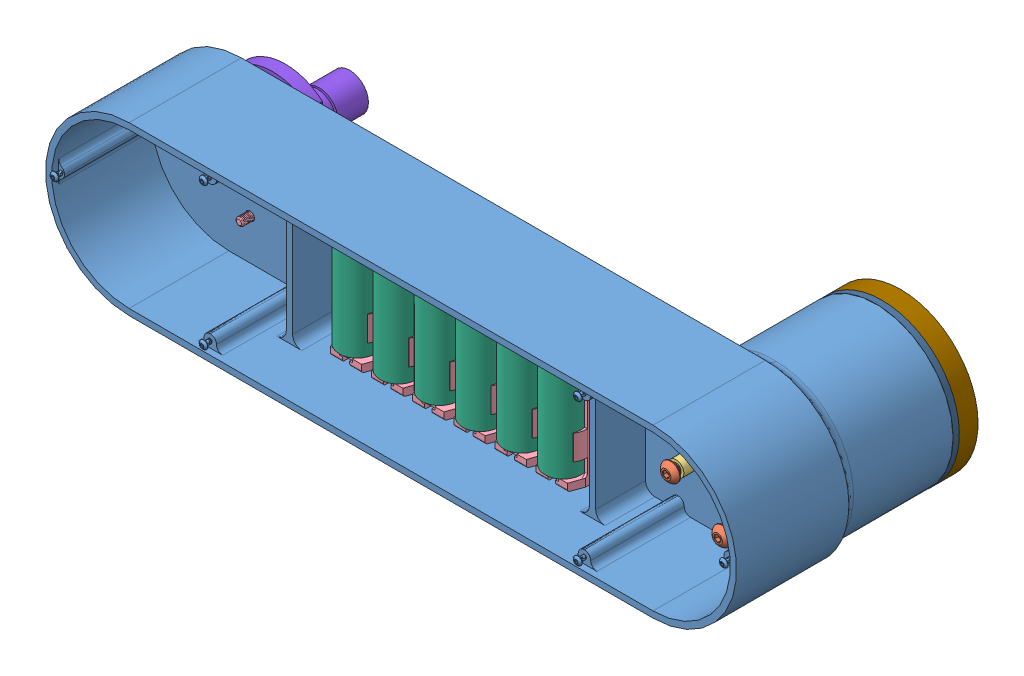
SolidWorks assembly Motor Link, configuration Default. Lengths in mm.
Overall size (351.79 85.09 127.3).
68 component instances, 28 part files, 118 mates.
Components (placement in the parent):
- Motor Link Frame-1: Motor Link Frame [Default] at (-50.4139 21.6178 -80.676) size (351.79 85.09 113.36)
- EC60 Motor-1: EC60 Motor [Default] at (-50.4139 21.6178 -74.326) x (0 0 1) z (0.866025 0.5 0) size (61.3 68 68) (hidden)
- Magnet Encoders E3-X-750-X-H-D-X-1: Magnet Encoders E3-X-750-X-H-D-X [Default] at (216.2861 21.6178 -70.897) x (0 -1 0) z (-1 0 0) size (55.98 16.26 66.52) (hidden)
- EM237 Magnet-1: EM237 Magnet [Default] at (216.2861 21.6178 -135.4915) x (0.985716 -0.168418 0) z (0.168418 0.985716 0) size (60.08 25.02 60.08)
- magnet holder-1: magnet holder [Default] at (219.7691 19.6509 -122.982) x (0.870755 -0.491717 0) z (-0.491717 -0.870755 0) size (50.8 63.9 50.6)
- PCB_Battery Assembly-3: PCB_Battery Assembly [Default] at (168.3898 -0.0136 45.5715) x (1 0 0) z (0 1 0) size (138.43 24.87 77.22)
  - Battery Holder - keystone-PN1043-1: Battery Holder - keystone-PN1043 [Default] at (-125.3925 103.3982 18.9155) x (1 0 0) z (0 0 -1) size (20.65 18.93 77.14)
  - Battery PCB-1: Battery PCB [Default] at (-148.3186 115.135 -16.9005) x (1 0 0) z (0 -1 0) size (138.43 77.06 1.59)
  - battery_6612-1: battery_6612 [Default] at (-117.0385 104.4035 -11.3639) x (-0.413992 0.91028 0) z (0.91028 0.413992 0) size (18.3 65.05 18.3)
  - battery_6612-2: battery_6612 [Default] at (-137.9935 104.4035 54.6265) x (-0.916106 0.400937 0) z (-0.400937 -0.916106 0) size (18.3 65.05 18.3)
  - Battery Holder - keystone-PN1043-2: Battery Holder - keystone-PN1043 [Default] at (-129.6396 103.3982 24.3471) x (-1 0 0) z (0 0 1) size (20.65 18.93 77.14)
  - Battery Holder - keystone-PN1043-3: Battery Holder - keystone-PN1043 [Default] at (-104.4375 103.3982 18.9155) x (1 0 0) z (0 0 -1) size (20.65 18.93 77.14)
  - battery_6612-3: battery_6612 [Default] at (-96.0835 104.4035 -10.3735) x (1 0 0) z (0 -1 0) size (18.3 65.05 18.3)
  - Battery Holder - keystone-PN1043-4: Battery Holder - keystone-PN1043 [Default] at (-83.4825 103.3982 18.9155) x (1 0 0) z (0 0 -1) size (20.65 18.93 77.14)
  - Battery Holder - keystone-PN1043-5: Battery Holder - keystone-PN1043 [Default] at (-45.8196 103.3982 24.3471) x (-1 0 0) z (0 0 1) size (20.65 18.93 77.14)
  - Battery Holder - keystone-PN1043-6: Battery Holder - keystone-PN1043 [Default] at (-41.5725 103.3982 18.9155) x (1 0 0) z (0 0 -1) size (20.65 18.93 77.14)
  - battery_6612-4: battery_6612 [Default] at (-75.1285 104.4035 -11.3639) x (-0.923728 -0.383049 0) z (-0.383049 0.923728 0) size (18.3 65.05 18.3)
  - battery_6612-5: battery_6612 [Default] at (-54.1735 104.4035 54.6265) x (-1 0 0) z (0 -1 0) size (18.3 65.05 18.3)
  - battery_6612-6: battery_6612 [Default] at (-33.2185 104.4035 -11.3639) x (-0.923728 -0.383049 0) z (-0.383049 0.923728 0) size (18.3 65.05 18.3)
- carrier_shaft-1: carrier_shaft [Default] at (-50.4139 39.1178 -75.596) x (-0.887515 0.46078 0) z (-0.46078 -0.887515 0) size (9 25.81 9)
- carrier_shaft-2: carrier_shaft [Default] at (-50.4139 4.1178 -75.596) x (-0.791269 0.611469 0) z (-0.611469 -0.791269 0) size (9 25.81 9)
- Shaft_Carrier_Combined-1: Shaft_Carrier_Combined [Default] at (-50.4139 21.6178 -103.1385) x (0 1 0) z (-1 0 0) size (57.15 55.17 57.15)
- Delrin_Ring-1: Delrin_Ring [Default] at (216.2861 21.6178 -149.5885) x (1 0 0) z (0 -1 0) size (78.74 9.53 78.74)
- Neoprene Ring-1: Neoprene Ring [Default] at (216.2861 21.6178 -140.0635) x (1 0 0) z (0 -1 0) size (78.74 3.17 78.74)
- Motor Link Acrylic Cover-1: Motor Link Acrylic Cover [Default] at (216.2861 21.6178 -26.701) x (-1 0 0) z (0 1 0) size (345.44 3.17 78.74) (hidden)
- Slip Ring M322M1-0600-1: Slip Ring M322M1-0600 [Default] at (216.2861 21.6178 -50.305) x (-0.866025 -0.5 0) z (0 0 -1) size (44 44 48) (hidden)
- bearing_8mmID_mcmaster_7804K115-1: bearing_8mmID_mcmaster_7804K115 [7804K115] at (-50.4139 39.1178 -78.926) x (-0.923728 -0.383049 0) z (0 0 -1) size (12 12 3.5)
- bearing_8mmID_mcmaster_7804K115-2: bearing_8mmID_mcmaster_7804K115 [7804K115] at (-50.4139 4.1178 -78.926) x (0.919429 -0.393256 0) z (0 0 -1) size (12 12 3.5)
- Bearing-I8mmO16mm-1: Bearing-I8mmO16mm [7804K117] at (-50.4139 4.1178 -99.051) x (0.999987 0.005155 0) z (0 0 1) size (16 16 5)
- Bearing-I8mmO16mm-2: Bearing-I8mmO16mm [7804K117] at (-50.4139 39.1178 -99.051) x (0.862389 -0.506247 0) z (0 0 -1) size (16 16 5)
- Bearing - .750-1: Bearing - .750 [3760T241] at (216.2861 21.6178 -86.2323) x (-0.324728 0.945808 0) z (0 0 1) size (41.27 41.27 11.11)
- Bearing - .750-2: Bearing - .750 [3760T241] at (216.2861 21.6178 -97.3448) x (0.923728 0.383049 0) z (0 0 -1) size (41.27 41.27 11.11)
- 10-32 Button Cap Thread Locking Screw-1: 10-32 Button Cap Thread Locking Screw [92360A244] at (-26.9189 13.9978 -89.5914) x (-0.890787 -0.45442 0) z (0 0 -1) size (9.17 9.17 12.51)
- 10-32 Button Cap Thread Locking Screw-2: 10-32 Button Cap Thread Locking Screw [92360A244] at (-73.9089 13.9978 -89.5914) x (-0.923728 -0.383049 0) z (0 0 -1) size (9.17 9.17 12.51)
- 10-32 Button Cap Thread Locking Screw-3: 10-32 Button Cap Thread Locking Screw [92360A244] at (-26.9189 29.2378 -89.5914) x (-0.923728 -0.383049 0) z (0 0 -1) size (9.17 9.17 12.51)
- 10-32 Button Cap Thread Locking Screw-4: 10-32 Button Cap Thread Locking Screw [92360A244] at (-73.9089 29.2378 -89.5914) x (-0.923728 -0.383049 0) z (0 0 -1) size (9.17 9.17 12.51)
- 1.625 Bore Internal Retaining Ring-1: 1.625 Bore Internal Retaining Ring [99142A560] at (216.2861 21.6178 -103.0534) x (1 0 0) z (0 -1 0) size (45.82 1.57 43.68)
- M8_L16mm Screws-1: M8_L16mm Screws [91760A423] at (216.2861 21.6178 -132.632) x (0.923728 0.383049 0) z (0 0 -1) size (13 13 24.67)
- .75 Bore External Retaining Ring-1: .75 Bore External Retaining Ring [97633A250] at (216.2861 21.6178 -80.1426) x (0 0 1) z (0.923728 0.383049 0) size (1.07 23.39 21.18)
- Dowel Pin - .0625-1: Dowel Pin - .0625 [97395A414] at (216.2861 57.8128 -133.7135) x (0 0 1) z (-1 0 0) size (19.05 1.59 1.59)
- Dowel Pin - .0625-2: Dowel Pin - .0625 [97395A414] at (252.4811 21.6178 -133.7135) x (0 0 1) z (-1 0 0) size (19.05 1.59 1.59)
- Dowel Pin - .0625-3: Dowel Pin - .0625 [97395A414] at (216.2861 -14.5772 -133.7135) x (0 0 1) z (-1 0 0) size (19.05 1.59 1.59)
- Dowel Pin - .0625-4: Dowel Pin - .0625 [97395A414] at (180.0911 21.6178 -133.7135) x (0 0 1) z (-1 0 0) size (19.05 1.59 1.59)
- 2-56 Screw-1: 2-56 Screw [98164A427] at (-88.1964 21.6178 -22.3576) size (4.17 4.17 10.95)
- 2-56 Screw-2: 2-56 Screw [98164A427] at (-12.3139 57.8128 -22.3576) size (4.17 4.17 10.95)
- 2-56 Screw-3: 2-56 Screw [98164A427] at (-12.3139 -14.5772 -22.3576) size (4.17 4.17 10.95)
- 2-56 Screw-4: 2-56 Screw [98164A427] at (178.1861 -14.5772 -22.3576) size (4.17 4.17 10.95)
- 2-56 Screw-5: 2-56 Screw [98164A427] at (252.4811 21.6178 -22.3576) size (4.17 4.17 10.95)
- 2-56 Screw-6: 2-56 Screw [98164A427] at (178.1861 57.8128 -22.3576) size (4.17 4.17 10.95)
- M5 Screws-1: M5 Screws [91352A131] at (225.0361 36.7732 -47.555) size (9.5 9.5 13.21)
- M5 Screws-2: M5 Screws [91352A131] at (225.0361 6.4623 -47.555) size (9.5 9.5 13.21)
- M5 Screws-3: M5 Screws [91352A131] at (198.7861 21.6178 -47.555) size (9.5 9.5 13.21)
- M5 Nylon Spacer-1: M5 Nylon Spacer [93657A042] at (198.7861 21.6178 -55.705) size (8 8 6)
- M5 Nylon Spacer-2: M5 Nylon Spacer [93657A042] at (225.0361 6.4623 -55.705) x (-0.923728 -0.383049 0) z (0 0 -1) size (8 8 6)
- M5 Nylon Spacer-3: M5 Nylon Spacer [93657A042] at (225.0361 36.7732 -55.705) size (8 8 6)
- M4 Screw-1: M4 Screw [91502A123] at (-71.9139 21.6178 -68.676) size (7 7 12.31)
- M4 Screw-2: M4 Screw [91502A123] at (-39.6639 40.2373 -68.676) size (7 7 12.31)
- M4 Screw-3: M4 Screw [91502A123] at (-39.6639 2.9982 -68.676) size (7 7 12.31)
- 4-40 Screws-1: 4-40 Screws [92949A108] at (216.2861 -1.3946 -69.3984) size (5.41 5.41 11.35)
- 4-40 Screws-2: 4-40 Screws [92949A108] at (216.2861 44.6302 -69.3984) size (5.41 5.41 11.35)
- 2-56 Screw-7: 2-56 Screw [98164A427] at (16.8961 53.7996 -66.8076) size (4.17 4.17 10.95)
- 2-56 Screw-8: 2-56 Screw [98164A427] at (148.9761 53.7996 -66.8076) size (4.17 4.17 10.95)
- 2-56 Screw-9: 2-56 Screw [98164A427] at (148.9761 -10.564 -66.8076) size (4.17 4.17 10.95)
- 2-56 Screw-10: 2-56 Screw [98164A427] at (16.8961 -10.564 -66.8076) size (4.17 4.17 10.95)
- #2 Spacer-1: #2 Spacer [94639A188] at (16.8961 -10.564 -71.9448) x (0.923728 0.383049 0) z (0 0 -1) size (6.35 6.35 4.76)
- #2 Spacer-2: #2 Spacer [94639A188] at (148.9761 -10.564 -71.9448) x (0.923728 0.383049 0) z (0 0 -1) size (6.35 6.35 4.76)
- #2 Spacer-3: #2 Spacer [94639A188] at (148.9761 53.7996 -71.9448) x (0.923728 0.383049 0) z (0 0 -1) size (6.35 6.35 4.76)
- #2 Spacer-4: #2 Spacer [94639A188] at (16.8961 53.7996 -71.9448) x (0.923728 0.383049 0) z (0 0 -1) size (6.35 6.35 4.76)
Mates (geometry in assembly coordinates):
- Coincident2: coincident aligned: line of Motor Link Frame-1 through (-50.4139 21.6178 -80.676) axis (0 0 1); line of EC60 Motor-1 through (-50.4139 21.6178 -95.9581) axis (0 0 1)
- Coincident3: coincident anti-aligned: plane of Motor Link Frame-1 through (-50.4139 21.6178 -74.326) normal (0 0 1); plane of EC60 Motor-1
- Coincident4: coincident aligned: plane of Motor Link Frame-1 through (-50.4139 21.6178 -80.676) normal (0 0 -1); plane of bearing_8mmID_mcmaster_7804K115-1 through (-50.4139 39.1178 -80.676) normal (0 0 -1)
- Coincident5: coincident aligned: line of Motor Link Frame-1 through (-50.4139 39.1178 -80.676) axis (0 0 1); line of bearing_8mmID_mcmaster_7804K115-1 through (-50.4139 39.1178 -77.176) axis (0 0 1)
- Coincident6: coincident aligned: plane of Motor Link Frame-1 through (-50.4139 21.6178 -80.676) normal (0 0 -1); plane of bearing_8mmID_mcmaster_7804K115-2 through (-50.4139 4.1178 -80.676) normal (0 0 -1)
- Coincident7: coincident aligned: line of Motor Link Frame-1 through (-50.4139 4.1178 -80.676) axis (0 0 1); line of bearing_8mmID_mcmaster_7804K115-2 through (-50.4139 4.1178 -77.176) axis (0 0 1)
- Concentric1: concentric: point of Motor Link Frame-1; cylinder of Magnet Encoders E3-X-750-X-H-D-X-1 through (216.2861 21.6178 -64.3438) axis (0 0 1) radius 9.5263
- Coincident11: coincident anti-aligned: plane of Motor Link Frame-1 through (-50.4139 21.6178 -74.326) normal (0 0 1); plane of Magnet Encoders E3-X-750-X-H-D-X-1 through (216.2861 21.6178 -74.326) normal (0 0 -1)
- Perpendicular1: perpendicular: plane of Motor Link Frame-1 through (-50.4139 64.1628 -80.676) normal (0 1 0); plane of Magnet Encoders E3-X-750-X-H-D-X-1 through (183.0629 6.0623 -72.4718) normal (-0.999391 0 0.034899)
- Concentric2: concentric aligned: line of Motor Link Frame-1 through (216.2861 21.6178 -136.8885) axis (0 0 1); cylinder of EM237 Magnet-1 through (216.2861 21.6178 -148.001) axis (0 0 1) radius 30.0419
- Coincident16: coincident anti-aligned: line of Motor Link Frame-1 through (216.2861 21.6178 -136.8885) axis (0 0 1); line of magnet holder-1 through (216.2861 21.6178 -59.086) axis (0 0 -1)
- Coincident26: coincident aligned: line of carrier_shaft-1 through (-50.4139 39.1178 -92.596) axis (0 0 1); line of Motor Link Frame-1 through (-50.4139 39.1178 -80.676) axis (0 0 1)
- Coincident29: coincident aligned: line of Motor Link Frame-1 through (-50.4139 4.1178 -80.676) axis (0 0 1); line of carrier_shaft-2 through (-50.4139 4.1178 -92.596) axis (0 0 1)
- Coincident37: coincident aligned: line of Motor Link Frame-1 through (-50.4139 21.6178 -80.676) axis (0 0 1); line of Shaft_Carrier_Combined-1 through (-50.4139 21.6178 -135.841) axis (0 0 1)
- Coincident38: coincident aligned: line of Motor Link Frame-1 through (-50.4139 4.1178 -80.676) axis (0 0 1); line of Shaft_Carrier_Combined-1 through (-50.4139 4.1178 -101.551) axis (0 0 1)
- Coincident39: coincident aligned: line of Motor Link Frame-1 through (-50.4139 39.1178 -80.676) axis (0 0 1); line of Shaft_Carrier_Combined-1 through (-50.4139 39.1178 -101.551) axis (0 0 1)
- Coincident41: coincident anti-aligned: plane of Motor Link Frame-1 through (-50.4139 21.6178 -80.676) normal (0 0 -1); plane of Shaft_Carrier_Combined-1
- Coincident42: coincident anti-aligned: line of Shaft_Carrier_Combined-1 through (-50.4139 4.1178 -101.551) axis (0 0 1); line of Bearing-I8mmO16mm-1 through (-50.4139 4.1178 -101.551) axis (0 0 -1)
- Coincident44: coincident aligned: line of Shaft_Carrier_Combined-1 through (-50.4139 39.1178 -101.551) axis (0 0 1); line of Bearing-I8mmO16mm-2 through (-50.4139 39.1178 -96.551) axis (0 0 1)
- Coincident46: coincident anti-aligned: plane of Motor Link Frame-1 through (-50.4139 39.1178 -75.596) normal (0 0 -1); plane of carrier_shaft-1 through (-50.4139 39.1178 -75.596) normal (0 0 1)
- Coincident47: coincident anti-aligned: plane of Motor Link Frame-1 through (-50.4139 4.1178 -75.596) normal (0 0 -1); plane of carrier_shaft-2 through (-50.4139 4.1178 -75.596) normal (0 0 1)
- Coincident51: coincident anti-aligned: plane of Shaft_Carrier_Combined-1 through (-50.4139 4.1178 -101.551) normal (0 0 1); plane of Bearing-I8mmO16mm-1 through (-50.4538 11.8676 -101.551) normal (0 0 -1)
- Coincident52: coincident anti-aligned: plane of Shaft_Carrier_Combined-1 through (-50.4139 39.1178 -101.551) normal (0 0 1); plane of Bearing-I8mmO16mm-2 through (-54.3373 32.4342 -101.551) normal (0 0 -1)
- Coincident53: coincident aligned: line of Motor Link Frame-1 through (-26.9189 13.9978 -76.866) axis (0 0 -1); line of 10-32 Button Cap Thread Locking Screw-1 through (-26.9189 13.9978 -77.501) axis (0 0 -1)
- Coincident54: coincident anti-aligned: plane of Shaft_Carrier_Combined-1 through (-50.4139 21.6178 -87.026) normal (0 0 -1); plane of 10-32 Button Cap Thread Locking Screw-1 through (-24.8355 9.9138 -87.026) normal (0 0 1)
- Coincident55: coincident anti-aligned: plane of Shaft_Carrier_Combined-1 through (-50.4139 21.6178 -87.026) normal (0 0 -1); plane of 10-32 Button Cap Thread Locking Screw-3 through (-25.1627 25.0027 -87.026) normal (0 0 1)
- Coincident56: coincident aligned: line of Motor Link Frame-1 through (-26.9189 29.2378 -76.866) axis (0 0 -1); line of 10-32 Button Cap Thread Locking Screw-3 through (-26.9189 29.2378 -77.501) axis (0 0 -1)
- Coincident57: coincident aligned: line of Motor Link Frame-1 through (-73.9089 13.9978 -76.866) axis (0 0 -1); line of 10-32 Button Cap Thread Locking Screw-2 through (-73.9089 13.9978 -77.501) axis (0 0 -1)
- Coincident58: coincident anti-aligned: plane of Shaft_Carrier_Combined-1 through (-50.4139 21.6178 -87.026) normal (0 0 -1); plane of 10-32 Button Cap Thread Locking Screw-2 through (-72.1527 9.7627 -87.026) normal (0 0 1)
- Coincident59: coincident aligned: line of Motor Link Frame-1 through (-73.9089 29.2378 -76.866) axis (0 0 -1); line of 10-32 Button Cap Thread Locking Screw-4 through (-73.9089 29.2378 -77.501) axis (0 0 -1)
- Coincident60: coincident anti-aligned: plane of Shaft_Carrier_Combined-1 through (-50.4139 21.6178 -87.026) normal (0 0 -1); plane of 10-32 Button Cap Thread Locking Screw-4 through (-72.1527 25.0027 -87.026) normal (0 0 1)
- Coincident61: coincident anti-aligned: line of Motor Link Frame-1 through (216.2861 21.6178 -136.8885) axis (0 0 1); line of Bearing - .750-1 through (216.2861 21.6178 -91.7885) axis (0 0 -1)
- Coincident62: coincident anti-aligned: plane of Motor Link Frame-1 through (216.2861 21.6178 -80.676) normal (0 0 -1); plane of Bearing - .750-1 through (197.2925 15.0966 -80.676) normal (0 0 1)
- Concentric6: concentric aligned: line of Motor Link Frame-1 through (216.2861 21.6178 -136.8885) axis (0 0 1); cylinder of 1.625 Bore Internal Retaining Ring-1 through (216.2861 21.6178 -104.6282) axis (0 0 1) radius 22.9108
- Concentric8: concentric anti-aligned: line of Motor Link Frame-1 through (216.2861 21.6178 -136.8885) axis (0 0 1); cylinder of Bearing - .750-2 through (216.2861 21.6178 -102.901) axis (0 0 -1) radius 9.525
- Coincident68: coincident anti-aligned: plane of Motor Link Frame-1 through (216.2861 21.6178 -104.6282) normal (0 0 1); plane of 1.625 Bore Internal Retaining Ring-1 through (227.2749 4.8737 -104.6282) normal (0 0 -1)
- Coincident69: coincident anti-aligned: plane of Bearing - .750-1 through (197.2925 15.0966 -91.7885) normal (0 0 -1); plane of Bearing - .750-2 through (223.9785 3.0676 -91.7885) normal (0 0 1)
- Coincident71: coincident anti-aligned: plane of magnet holder-1 through (227.3447 15.3729 -102.901) normal (0 0 1); plane of Bearing - .750-2 through (221.5551 8.9115 -102.901) normal (0 0 -1)
- Coincident72: coincident anti-aligned: plane of EM237 Magnet-1 through (216.2861 21.6178 -122.982) normal (0 0 1); plane of magnet holder-1 through (219.7691 19.6509 -122.982) normal (0 0 -1)
- Concentric9: concentric aligned: line of magnet holder-1 through (216.2861 21.6178 -59.086) axis (0 0 -1); cylinder of M8_L16mm Screws-1 through (216.2861 21.6178 -108.632) axis (0 0 -1) radius 6.5
- Coincident74: coincident anti-aligned: plane of magnet holder-1 through (222.161 18.3002 -116.632) normal (0 0 1); plane of M8_L16mm Screws-1 through (216.2861 21.6178 -116.632) normal (0 0 -1)
- Concentric10: concentric aligned: line of magnet holder-1 through (216.2861 21.6178 -59.086) axis (0 0 -1); cylinder of .75 Bore External Retaining Ring-1 through (216.2861 21.6178 -79.6092) axis (0 0 -1) radius 8.8011
- Coincident77: coincident anti-aligned: plane of magnet holder-1 through (216.2861 21.6178 -80.676) normal (0 0 1); plane of .75 Bore External Retaining Ring-1 through (216.2861 21.6178 -80.676) normal (0 0 -1)
- Coincident78: coincident anti-aligned: plane of Motor Link Frame-1 through (216.2861 21.6178 -136.8885) normal (0 0 -1); plane of Neoprene Ring-1 through (216.2861 21.6178 -136.8885) normal (0 0 1)
- Concentric11: concentric anti-aligned: line of Motor Link Frame-1 through (216.2861 21.6178 -136.8885) axis (0 0 1); cylinder of Neoprene Ring-1 through (216.2861 21.6178 -136.8885) axis (0 0 -1) radius 33.02
- Concentric12: concentric anti-aligned: line of Motor Link Frame-1 through (216.2861 21.6178 -136.8885) axis (0 0 1); cylinder of Delrin_Ring-1 through (216.2861 21.6178 -140.0635) axis (0 0 -1) radius 33.02
- Coincident81: coincident anti-aligned: plane of Delrin_Ring-1 through (216.2861 21.6178 -140.0635) normal (0 0 1); plane of Neoprene Ring-1 through (216.2861 21.6178 -140.0635) normal (0 0 -1)
- Concentric13: concentric aligned: cylinder of Motor Link Frame-1 through (252.4811 21.6178 -124.1885) axis (0 0 -1) radius 0.7937; cylinder of Neoprene Ring-1 through (252.4811 21.6178 -136.8885) axis (0 0 -1) radius 0.7937
- Concentric14: concentric aligned: cylinder of Motor Link Frame-1 through (252.4811 21.6178 -124.1885) axis (0 0 -1) radius 0.7937; cylinder of Delrin_Ring-1 through (252.4811 21.6178 -140.0635) axis (0 0 -1) radius 0.7937
- Concentric15: concentric anti-aligned: cylinder of Motor Link Frame-1 through (252.4811 21.6178 -124.1885) axis (0 0 -1) radius 0.7937; cylinder of Dowel Pin - .0625-2 through (252.4811 21.6178 -143.2385) axis (0 0 1) radius 0.7937
- Coincident82: coincident anti-aligned: plane of Motor Link Frame-1 through (252.4811 21.6178 -124.1885) normal (0 0 -1); plane of Dowel Pin - .0625-2 through (252.4811 21.6178 -124.1885) normal (0 0 1)
- Concentric16: concentric anti-aligned: cylinder of Motor Link Frame-1 through (216.2861 57.8128 -124.1885) axis (0 0 -1) radius 0.7937; cylinder of Dowel Pin - .0625-1 through (216.2861 57.8128 -143.2385) axis (0 0 1) radius 0.7937
- Coincident83: coincident anti-aligned: plane of Motor Link Frame-1 through (216.2861 57.8128 -124.1885) normal (0 0 -1); plane of Dowel Pin - .0625-1 through (216.2861 57.8128 -124.1885) normal (0 0 1)
- Concentric17: concentric anti-aligned: cylinder of Motor Link Frame-1 through (180.0911 21.6178 -124.1885) axis (0 0 -1) radius 0.7937; cylinder of Dowel Pin - .0625-4 through (180.0911 21.6178 -143.2385) axis (0 0 1) radius 0.7937
- Coincident84: coincident anti-aligned: plane of Motor Link Frame-1 through (180.0911 21.6178 -124.1885) normal (0 0 -1); plane of Dowel Pin - .0625-4 through (180.0911 21.6178 -124.1885) normal (0 0 1)
- Concentric18: concentric anti-aligned: cylinder of Motor Link Frame-1 through (216.2861 -14.5772 -124.1885) axis (0 0 -1) radius 0.7937; cylinder of Dowel Pin - .0625-3 through (216.2861 -14.5772 -143.2385) axis (0 0 1) radius 0.7937
- Coincident85: coincident anti-aligned: plane of Motor Link Frame-1 through (216.2861 -14.5772 -124.1885) normal (0 0 -1); plane of Dowel Pin - .0625-3 through (216.2861 -14.5772 -124.1885) normal (0 0 1)
- Coincident86: coincident anti-aligned: plane of Motor Link Acrylic Cover-1 through (216.2861 21.6178 -26.701) normal (0 0 -1); plane of Motor Link Frame-1 through (-50.4139 21.6178 -26.701) normal (0 0 1)
- Concentric26: concentric anti-aligned: cylinder of Motor Link Frame-1 through (-88.1964 21.6178 -26.701) axis (0 0 1) radius 0.889; cylinder of Motor Link Acrylic Cover-1 through (-88.1964 21.6178 -23.526) axis (0 0 -1) radius 1.0922
- Concentric27: concentric anti-aligned: cylinder of Motor Link Frame-1 through (252.4811 21.6178 -26.701) axis (0 0 1) radius 0.889; cylinder of Motor Link Acrylic Cover-1 through (252.4811 21.6178 -23.526) axis (0 0 -1) radius 1.0922
- Concentric28: concentric anti-aligned: cylinder of Motor Link Acrylic Cover-1 through (-88.1964 21.6178 -23.526) axis (0 0 -1) radius 1.0922; line of 2-56 Screw-1 through (-88.1964 21.6178 -33.051) axis (0 0 1)
- Coincident88: coincident anti-aligned: plane of Motor Link Acrylic Cover-1 through (216.2861 21.6178 -23.526) normal (0 0 1); plane of 2-56 Screw-1 through (-88.1964 19.535 -23.526) normal (0 0 -1)
- Concentric29: concentric anti-aligned: cylinder of Motor Link Acrylic Cover-1 through (-12.3139 57.8128 -23.526) axis (0 0 -1) radius 1.0922; line of 2-56 Screw-2 through (-12.3139 57.8128 -33.051) axis (0 0 1)
- Coincident90: coincident anti-aligned: plane of Motor Link Acrylic Cover-1 through (216.2861 21.6178 -23.526) normal (0 0 1); plane of 2-56 Screw-2 through (-12.3139 55.73 -23.526) normal (0 0 -1)
- Concentric30: concentric anti-aligned: cylinder of Motor Link Acrylic Cover-1 through (-12.3139 -14.5772 -23.526) axis (0 0 -1) radius 1.0922; line of 2-56 Screw-3 through (-12.3139 -14.5772 -33.051) axis (0 0 1)
- Coincident92: coincident anti-aligned: plane of Motor Link Acrylic Cover-1 through (216.2861 21.6178 -23.526) normal (0 0 1); plane of 2-56 Screw-3 through (-12.3139 -16.66 -23.526) normal (0 0 -1)
- Concentric31: concentric anti-aligned: cylinder of Motor Link Acrylic Cover-1 through (178.1861 -14.5772 -23.526) axis (0 0 -1) radius 1.0922; line of 2-56 Screw-4 through (178.1861 -14.5772 -33.051) axis (0 0 1)
- Coincident94: coincident anti-aligned: plane of Motor Link Acrylic Cover-1 through (216.2861 21.6178 -23.526) normal (0 0 1); plane of 2-56 Screw-4 through (178.1861 -16.66 -23.526) normal (0 0 -1)
- Concentric32: concentric anti-aligned: cylinder of Motor Link Acrylic Cover-1 through (178.1861 57.8128 -23.526) axis (0 0 -1) radius 1.0922; line of 2-56 Screw-6 through (178.1861 57.8128 -33.051) axis (0 0 1)
- Coincident96: coincident anti-aligned: plane of Motor Link Acrylic Cover-1 through (216.2861 21.6178 -23.526) normal (0 0 1); plane of 2-56 Screw-6 through (178.1861 55.73 -23.526) normal (0 0 -1)
- Concentric33: concentric anti-aligned: cylinder of Motor Link Acrylic Cover-1 through (252.4811 21.6178 -23.526) axis (0 0 -1) radius 1.0922; line of 2-56 Screw-5 through (252.4811 21.6178 -33.051) axis (0 0 1)
- Coincident98: coincident anti-aligned: plane of Motor Link Acrylic Cover-1 through (216.2861 21.6178 -23.526) normal (0 0 1); plane of 2-56 Screw-5 through (252.4811 19.535 -23.526) normal (0 0 -1)
- Distance2: distance = 6 mm anti-aligned: plane of Slip Ring M322M1-0600-1 through (197.2336 10.6178 -52.705) normal (0 0 -1); plane of Magnet Encoders E3-X-750-X-H-D-X-1 through (216.2861 21.6178 -58.705) normal (0 0 1)
- Concentric34: concentric aligned: line of Motor Link Frame-1 through (216.2861 21.6178 -136.8885) axis (0 0 1); cylinder of Slip Ring M322M1-0600-1 through (216.2861 21.6178 -66.705) axis (0 0 1) radius 3.8
- Concentric35: concentric aligned: cylinder of Slip Ring M322M1-0600-1 through (198.7861 21.6178 -50.305) axis (0 0 1) radius 2.75; cylinder of Magnet Encoders E3-X-750-X-H-D-X-1 through (198.7861 21.6178 -58.705) axis (0 0 1) radius 2.1
- Concentric36: concentric aligned: cylinder of Magnet Encoders E3-X-750-X-H-D-X-1 through (225.0361 6.4623 -58.705) axis (0 0 1) radius 2.1; cylinder of Slip Ring M322M1-0600-1 through (225.0361 6.4623 -50.305) axis (0 0 1) radius 2.75
- Concentric37: concentric aligned: cylinder of Magnet Encoders E3-X-750-X-H-D-X-1 through (225.0361 36.7732 -58.705) axis (0 0 1) radius 2.1; cylinder of Slip Ring M322M1-0600-1 through (225.0361 36.7732 -50.305) axis (0 0 1) radius 2.75
- Concentric38: concentric aligned: cylinder of Slip Ring M322M1-0600-1 through (225.0361 36.7732 -50.305) axis (0 0 1) radius 2.75; line of M5 Screws-1 through (225.0361 36.7732 -60.305) axis (0 0 1)
- Coincident102: coincident anti-aligned: plane of Slip Ring M322M1-0600-1 through (216.2861 21.6178 -50.305) normal (0 0 1); plane of M5 Screws-1 through (225.0361 32.0232 -50.305) normal (0 0 -1)
- Concentric39: concentric aligned: cylinder of Slip Ring M322M1-0600-1 through (225.0361 6.4623 -50.305) axis (0 0 1) radius 2.75; line of M5 Screws-2 through (225.0361 6.4623 -60.305) axis (0 0 1)
- Coincident104: coincident anti-aligned: plane of Slip Ring M322M1-0600-1 through (216.2861 21.6178 -50.305) normal (0 0 1); plane of M5 Screws-2 through (225.0361 1.7123 -50.305) normal (0 0 -1)
- Concentric40: concentric aligned: cylinder of Slip Ring M322M1-0600-1 through (198.7861 21.6178 -50.305) axis (0 0 1) radius 2.75; line of M5 Screws-3 through (198.7861 21.6178 -60.305) axis (0 0 1)
- Coincident106: coincident anti-aligned: plane of Slip Ring M322M1-0600-1 through (216.2861 21.6178 -50.305) normal (0 0 1); plane of M5 Screws-3 through (198.7861 16.8678 -50.305) normal (0 0 -1)
- Coincident107: coincident anti-aligned: plane of Magnet Encoders E3-X-750-X-H-D-X-1 through (216.2861 21.6178 -58.705) normal (0 0 1); plane of M5 Nylon Spacer-1 through (198.7861 21.6178 -58.705) normal (0 0 -1)
- Concentric42: concentric aligned: cylinder of Slip Ring M322M1-0600-1 through (225.0361 6.4623 -50.305) axis (0 0 1) radius 2.75; cylinder of M5 Nylon Spacer-2 through (225.0361 6.4623 -58.705) axis (0 0 1) radius 2.65
- Coincident108: coincident anti-aligned: plane of Magnet Encoders E3-X-750-X-H-D-X-1 through (216.2861 21.6178 -58.705) normal (0 0 1); plane of M5 Nylon Spacer-2 through (225.0361 6.4623 -58.705) normal (0 0 -1)
- Concentric43: concentric anti-aligned: cylinder of Slip Ring M322M1-0600-1 through (225.0361 36.7732 -50.305) axis (0 0 1) radius 2.75; cylinder of M5 Nylon Spacer-3 through (225.0361 36.7732 -52.705) axis (0 0 -1) radius 2.65
- Coincident109: coincident anti-aligned: plane of Slip Ring M322M1-0600-1 through (197.2336 10.6178 -52.705) normal (0 0 -1); plane of M5 Nylon Spacer-3 through (225.0361 36.7732 -52.705) normal (0 0 1)
- Concentric44: concentric anti-aligned: cylinder of Motor Link Frame-1 through (-39.6639 2.9982 -80.676) axis (0 0 -1) radius 4; circle of M4 Screw-3
- Coincident111: coincident anti-aligned: plane of Motor Link Frame-1 through (-37.4139 2.9982 -76.676) normal (0 0 -1); plane of M4 Screw-3 through (-39.6639 2.9982 -76.676) normal (0 0 1)
- Concentric45: concentric anti-aligned: cylinder of Motor Link Frame-1 through (-39.6639 40.2373 -80.676) axis (0 0 -1) radius 4; cylinder of M4 Screw-2 through (-39.6639 40.2373 -80.676) axis (0 0 1) radius 3.5
- Coincident112: coincident anti-aligned: plane of Motor Link Frame-1 through (-37.4139 40.2373 -76.676) normal (0 0 -1); plane of M4 Screw-2 through (-39.6639 40.2373 -76.676) normal (0 0 1)
- Concentric47: concentric anti-aligned: cylinder of Motor Link Frame-1 through (-71.9139 21.6178 -80.676) axis (0 0 -1) radius 4; cylinder of M4 Screw-1 through (-71.9139 21.6178 -80.676) axis (0 0 1) radius 3.5
- Coincident113: coincident anti-aligned: plane of Motor Link Frame-1 through (-69.6639 21.6178 -76.676) normal (0 0 -1); plane of M4 Screw-1 through (-71.9139 21.6178 -76.676) normal (0 0 1)
- Concentric48: concentric aligned: cylinder of Motor Link Frame-1 through (-71.9139 21.6178 -80.676) axis (0 0 -1) radius 4; cylinder of EC60 Motor-1 through (-71.9139 21.6178 -74.326) axis (0 0 -1) radius 1.65
- Concentric49: concentric anti-aligned: cylinder of Magnet Encoders E3-X-750-X-H-D-X-1 through (216.2861 -1.3946 -70.897) axis (0 0 -1) radius 1.4351; line of 4-40 Screws-1 through (216.2861 -1.3946 -80.422) axis (0 0 1)
- Coincident115: coincident anti-aligned: plane of Magnet Encoders E3-X-750-X-H-D-X-1 through (216.2861 21.6178 -70.897) normal (0 0 1); plane of 4-40 Screws-1 through (216.2861 -4.0997 -70.897) normal (0 0 -1)
- Concentric50: concentric anti-aligned: cylinder of Magnet Encoders E3-X-750-X-H-D-X-1 through (216.2861 44.6302 -70.897) axis (0 0 -1) radius 1.4351; line of 4-40 Screws-2 through (216.2861 44.6302 -80.422) axis (0 0 1)
- Coincident117: coincident anti-aligned: plane of Magnet Encoders E3-X-750-X-H-D-X-1 through (216.2861 21.6178 -70.897) normal (0 0 1); plane of 4-40 Screws-2 through (216.2861 41.9251 -70.897) normal (0 0 -1)
- Concentric51: concentric anti-aligned: cylinder of PCB_Battery Assembly-3/Battery PCB-1 through (16.8961 53.7996 -67.976) axis (0 0 -1) radius 1.0922; cylinder of 2-56 Screw-7 through (16.8961 53.7996 -66.8076) axis (0 0 1) radius 2.0828
- Coincident118: coincident anti-aligned: plane of PCB_Battery Assembly-3/Battery PCB-1 through (20.0711 -16.914 -67.976) normal (0 0 1); plane of 2-56 Screw-7 through (16.8961 51.7168 -67.976) normal (0 0 -1)
- Concentric52: concentric anti-aligned: cylinder of PCB_Battery Assembly-3/Battery PCB-1 through (16.8961 -10.564 -67.976) axis (0 0 -1) radius 1.0922; cylinder of 2-56 Screw-10 through (16.8961 -10.564 -66.8076) axis (0 0 1) radius 2.0828
- Coincident119: coincident anti-aligned: plane of PCB_Battery Assembly-3/Battery PCB-1 through (20.0711 -16.914 -67.976) normal (0 0 1); plane of 2-56 Screw-10 through (16.8961 -12.6468 -67.976) normal (0 0 -1)
- Concentric53: concentric anti-aligned: cylinder of PCB_Battery Assembly-3/Battery PCB-1 through (148.9761 53.7996 -67.976) axis (0 0 -1) radius 1.0922; cylinder of 2-56 Screw-8 through (148.9761 53.7996 -66.8076) axis (0 0 1) radius 2.0828
- Coincident120: coincident anti-aligned: plane of PCB_Battery Assembly-3/Battery PCB-1 through (20.0711 -16.914 -67.976) normal (0 0 1); plane of 2-56 Screw-8 through (148.9761 51.7168 -67.976) normal (0 0 -1)
- Coincident121: coincident anti-aligned: plane of PCB_Battery Assembly-3/Battery PCB-1 through (20.0711 -16.914 -67.976) normal (0 0 1); plane of 2-56 Screw-9 through (148.9761 -12.6468 -67.976) normal (0 0 -1)
- Concentric54: concentric anti-aligned: cylinder of PCB_Battery Assembly-3/Battery PCB-1 through (148.9761 -10.564 -67.976) axis (0 0 -1) radius 1.0922; cylinder of 2-56 Screw-9 through (148.9761 -10.564 -66.8076) axis (0 0 1) radius 2.0828
- Concentric55: concentric aligned: cylinder of Motor Link Frame-1 through (148.9761 -10.564 -74.326) axis (0 0 1) radius 0.889; cylinder of #2 Spacer-2 through (148.9761 -10.564 -74.326) axis (0 0 1) radius 1.143
- Coincident122: coincident anti-aligned: plane of Motor Link Frame-1 through (-50.4139 21.6178 -74.326) normal (0 0 1); plane of #2 Spacer-2 through (148.9761 -10.564 -74.326) normal (0 0 -1)
- Concentric56: concentric aligned: cylinder of Motor Link Frame-1 through (148.9761 53.7996 -74.326) axis (0 0 1) radius 0.889; cylinder of #2 Spacer-3 through (148.9761 53.7996 -74.326) axis (0 0 1) radius 1.143
- Coincident123: coincident anti-aligned: plane of Motor Link Frame-1 through (-50.4139 21.6178 -74.326) normal (0 0 1); plane of #2 Spacer-3 through (148.9761 53.7996 -74.326) normal (0 0 -1)
- Concentric57: concentric aligned: cylinder of Motor Link Frame-1 through (16.8961 -10.564 -74.326) axis (0 0 1) radius 0.889; cylinder of #2 Spacer-1 through (16.8961 -10.564 -74.326) axis (0 0 1) radius 1.143
- Coincident124: coincident anti-aligned: plane of Motor Link Frame-1 through (-50.4139 21.6178 -74.326) normal (0 0 1); plane of #2 Spacer-1 through (16.8961 -10.564 -74.326) normal (0 0 -1)
- Concentric58: concentric aligned: cylinder of Motor Link Frame-1 through (16.8961 53.7996 -74.326) axis (0 0 1) radius 0.889; cylinder of #2 Spacer-4 through (16.8961 53.7996 -74.326) axis (0 0 1) radius 1.143
- Coincident125: coincident anti-aligned: plane of Motor Link Frame-1 through (-50.4139 21.6178 -74.326) normal (0 0 1); plane of #2 Spacer-4 through (16.8961 53.7996 -74.326) normal (0 0 -1)
- Coincident126: coincident anti-aligned: plane of PCB_Battery Assembly-3/Battery PCB-1 through (20.0711 -16.914 -69.5635) normal (0 0 -1); plane of #2 Spacer-1 through (16.8961 -10.564 -69.5635) normal (0 0 1)
- Concentric60: concentric anti-aligned: cylinder of Motor Link Frame-1 through (16.8961 53.7996 -74.326) axis (0 0 1) radius 0.889; cylinder of PCB_Battery Assembly-3/Battery PCB-1 through (16.8961 53.7996 -67.976) axis (0 0 -1) radius 1.0922
- Concentric61: concentric anti-aligned: cylinder of Motor Link Frame-1 through (16.8961 -10.564 -74.326) axis (0 0 1) radius 0.889; cylinder of PCB_Battery Assembly-3/Battery PCB-1 through (16.8961 -10.564 -67.976) axis (0 0 -1) radius 1.0922
